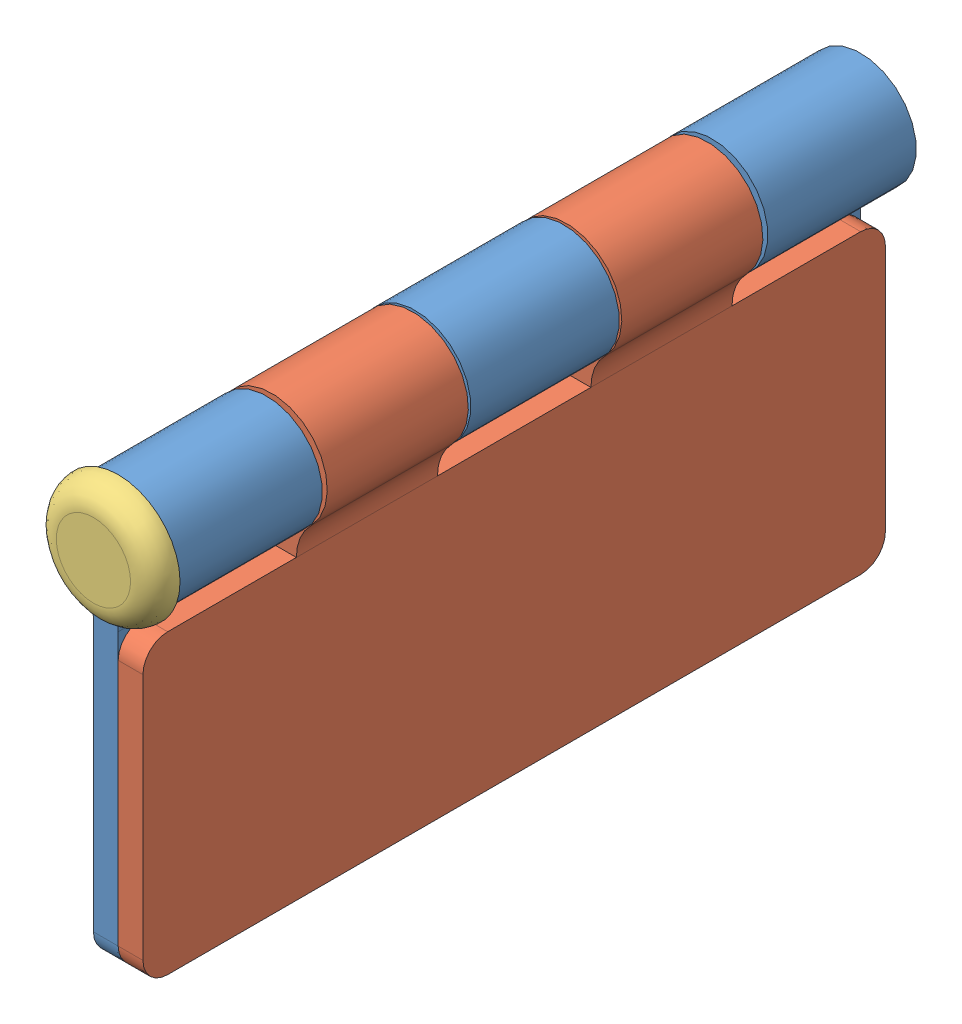
SolidWorks assembly Cockpit hinge, configuration Default. Lengths in mm.
Overall size (12.7 44.45 78.74).
3 component instances, 3 part files, 9 mates.
Components (placement in the parent):
- big hinge cockpit side-1: big hinge cockpit side [Default] at origin size (11.43 43.81 76.2)
- big hinge fueslage side-1: big hinge fueslage side [Default] at origin size (11.43 43.81 76.2)
- big hinge pin-2: big hinge pin [Default] at (0 38.1 40.64) x (0 0 1) z (-1 0 0) size (78.74 12.7 12.7)
Mates (geometry in assembly coordinates):
- Coincident2: coincident aligned: plane of big hinge cockpit side-1 through (0 0 0) normal (0 0 1)
- Coincident4: coincident aligned: plane of big hinge fueslage side-1 through (0 0 0) normal (0 0 1)
- Coincident5: coincident aligned: plane of big hinge fueslage side-1 through (0 0 0) normal (0 1 0)
- Coincident6: coincident aligned: plane of big hinge fueslage side-1 through (0 0 0) normal (1 0 0)
- Concentric1: concentric aligned: cylinder of big hinge cockpit side-1 through (0 38.1 38.1) axis (0 0 -1) radius 3.175; cylinder of big hinge fueslage side-1 through (0 38.1 38.1) axis (0 0 -1) radius 3.175
- Coincident7: coincident anti-aligned: plane of big hinge pin-1 through (0 0 0) normal (-1 0 0)
- Coincident8: coincident anti-aligned: plane of big hinge pin-2 through (0 38.1 40.64) normal (-1 0 0)
- Concentric2: concentric anti-aligned: cylinder of big hinge fueslage side-1 through (0 38.1 38.1) axis (0 0 -1) radius 3.175; cylinder of big hinge pin-2 through (0 38.1 40.64) axis (0 0 1) radius 3.175
- Coincident9: coincident anti-aligned: plane of big hinge cockpit side-1 through (0 0 38.1) normal (0 0 1); plane of big hinge pin-2 through (0 41.275 38.1) normal (0 0 -1)
